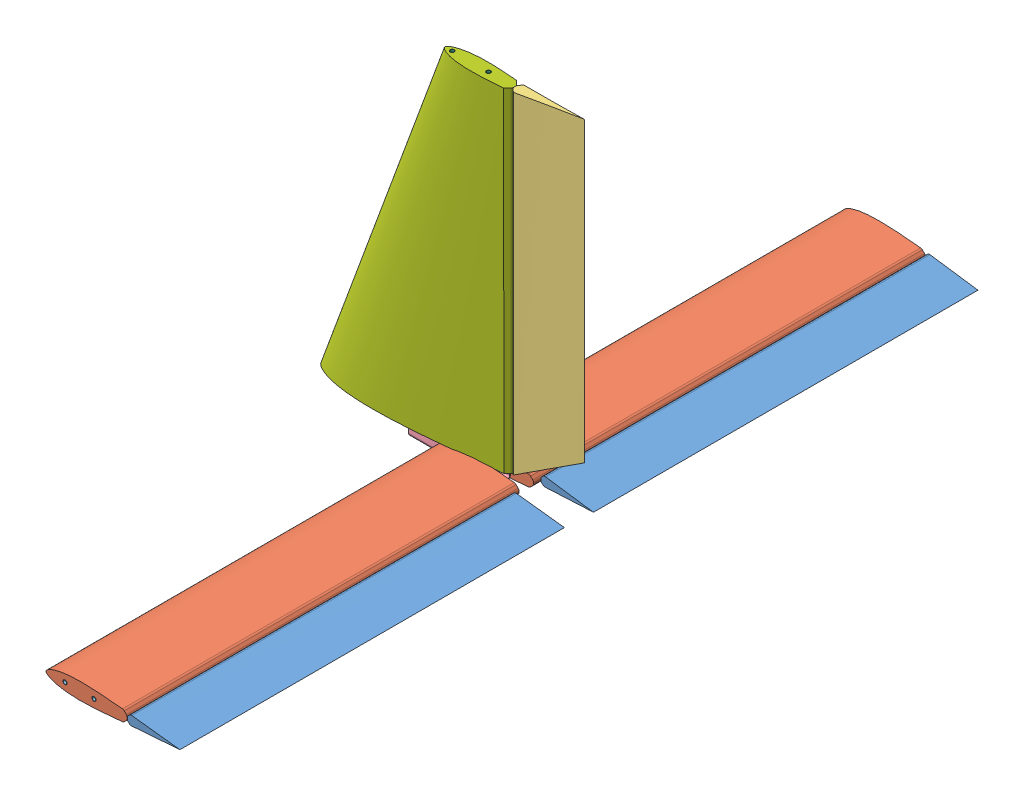
SolidWorks assembly Tail_Assembly, configuration Default. Lengths in mm.
Overall size (451.7 622.57 1397.12).
11 component instances, 7 part files, 24 mates.
Components (placement in the parent):
- Elevator-1: Elevator [Default] at (492.122 379.2937 1582.949) x (0.998942 -0.045988 -0.000487) z (0.000499 0.00026 1) size (92.08 16.15 673.1)
- Horizontal_stabilizer-1: Horizontal_stabilizer [Default] at (491.9754 372.5377 1589.3008) x (0.999999 0.001563 -0.0005) z (0.000499 0.00026 1) size (144.82 29.24 685.8)
- Rudder-1: Rudder [Default] at (492.4867 969.5335 1957.573) x (0.994379 0.000345 -0.105876) z (0.000374 -1 0.000259) size (113.98 20.6 584.38)
- Tail_attachment-1: Tail_attachment [Default] at (593.6259 372.668 1944.8501) x (0.000499 0.00026 1) z (0.000374 -1 0.000259) size (25.4 152.4 25.4)
- Tail_cf_rod_HS-1: Tail_cf_rod_HS [Default] at (576.4486 372.8428 2643.3587) x (0.998942 -0.045988 -0.000487) z (0.045988 0.998942 -0.000282) size (7.24 1397 7.24)
- Tail_cf_rod_VS-1: Tail_cf_rod_VS [Default] at (504.7355 347.2348 1944.9011) x (0.972062 0.000425 0.234724) z (-0.234724 0.000164 0.972062) size (7.24 622.3 7.24)
- Vetical_Stabilizer-1: Vetical_Stabilizer [Default] at (491.8026 969.5299 1944.746) x (1 0.000374 -0.000499) z (0.000374 -1 0.000259) size (337.04 56.71 584.54)
- Elevator-2: Elevator [Default] at (492.3655 375.9774 2306.8498) x (0.999772 -0.02133 -0.000493) z (0.000499 0.00026 1) size (92.08 16.15 673.1)
- Horizontal_stabilizer-2: Horizontal_stabilizer [Default] at (492.3304 372.7224 2300.5007) x (0.999999 0.001563 -0.0005) z (0.000499 0.00026 1) size (144.82 29.24 685.8)
- Tail_cf_rod_HS-2: Tail_cf_rod_HS [Default] at (525.6486 372.8238 2643.3841) x (0.998942 -0.045988 -0.000487) z (0.045988 0.998942 -0.000282) size (7.24 1397 7.24)
- Tail_cf_rod_VS-2: Tail_cf_rod_VS [Default] at (568.2354 347.2585 1944.8694) x (0.993671 0.000401 0.112329) z (-0.11233 0.000216 0.993671) size (7.24 622.3 7.24)
Mates (geometry in assembly coordinates):
- Concentric1: concentric anti-aligned: cylinder of Horizontal_stabilizer-1 through (525.2936 372.6391 1932.1852) axis (-0.000499 -0.00026 -1) radius 3.6; cylinder of Tail_cf_rod_HS-2 through (524.9513 372.4611 1246.3843) axis (0.000499 0.00026 1) radius 3.6195
- Concentric2: concentric anti-aligned: cylinder of Horizontal_stabilizer-2 through (525.6486 372.8238 2643.3851) axis (-0.000499 -0.00026 -1) radius 3.6; cylinder of Tail_cf_rod_HS-2 through (524.9513 372.4611 1246.3843) axis (0.000499 0.00026 1) radius 3.6195
- Coincident1: coincident anti-aligned: circle of Tail_attachment-1; cylinder of Tail_cf_rod_HS-2 through (524.9513 372.4611 1246.3843) axis (0.000499 0.00026 1) radius 3.6195
- Concentric3: concentric anti-aligned: cylinder of Tail_attachment-1 through (576.1063 372.6647 1957.5588) axis (-0.000499 -0.00026 -1) radius 3.6195; cylinder of Tail_cf_rod_HS-1 through (575.7513 372.4801 1246.3589) axis (0.000499 0.00026 1) radius 3.6195
- Concentric4: concentric anti-aligned: cylinder of Horizontal_stabilizer-1 through (576.0936 372.6581 1932.1598) axis (-0.000499 -0.00026 -1) radius 3.6; cylinder of Tail_cf_rod_HS-1 through (575.7513 372.4801 1246.3589) axis (0.000499 0.00026 1) radius 3.6195
- Concentric5: concentric anti-aligned: cylinder of Tail_cf_rod_HS-1 through (575.7513 372.4801 1246.3589) axis (0.000499 0.00026 1) radius 3.6195; cylinder of Horizontal_stabilizer-2 through (576.4486 372.8428 2643.3597) axis (-0.000499 -0.00026 -1) radius 3.6
- Concentric6: concentric anti-aligned: cylinder of Tail_cf_rod_VS-1 through (504.5026 969.5347 1944.7396) axis (0.000374 -1 0.000259) radius 3.6195; cylinder of Vetical_Stabilizer-1 through (504.7213 385.1657 1944.8912) axis (-0.000374 1 -0.000259) radius 3.6195
- Concentric7: concentric aligned: cylinder of Tail_attachment-1 through (568.2212 385.3585 1944.8595) axis (0.000374 -1 0.000259) radius 3.6195; cylinder of Tail_cf_rod_VS-2 through (568.0026 969.5584 1944.7079) axis (0.000374 -1 0.000259) radius 3.6195
- Concentric8: concentric anti-aligned: cylinder of Vetical_Stabilizer-1 through (568.2212 385.1894 1944.8595) axis (-0.000374 1 -0.000259) radius 3.6195; cylinder of Tail_cf_rod_VS-2 through (568.0026 969.5584 1944.7079) axis (0.000374 -1 0.000259) radius 3.6195
- Concentric9: concentric anti-aligned: cylinder of Tail_cf_rod_VS-1 through (504.5026 969.5347 1944.7396) axis (0.000374 -1 0.000259) radius 3.6195; cylinder of Vetical_Stabilizer-1 through (504.7213 385.1657 1944.8912) axis (-0.000374 1 -0.000259) radius 3.6195
- Coincident2: coincident aligned: plane of Horizontal_stabilizer-2 through (492.5015 372.8114 2643.4006) normal (0.000499 0.00026 1); plane of Tail_cf_rod_HS-2 through (525.6486 372.8238 2643.3841) normal (0.000499 0.00026 1)
- Coincident3: coincident anti-aligned: plane of Tail_attachment-1 through (441.2294 380.2343 1957.6242) normal (0.000499 0.00026 1); plane of Horizontal_stabilizer-2 through (492.1592 372.6333 1957.6007) normal (-0.000499 -0.00026 -1)
- Coincident4: coincident anti-aligned: plane of Horizontal_stabilizer-1 through (492.1465 372.6267 1932.2007) normal (0.000499 0.00026 1); plane of Tail_attachment-1 through (441.2168 380.2277 1932.2242) normal (-0.000499 -0.00026 -1)
- Coincident5: coincident anti-aligned: plane of Tail_attachment-1 through (441.2174 385.309 1937.3029) normal (-0.000374 1 -0.000259); plane of Vetical_Stabilizer-1 through (276.8789 385.2495 1945.0049) normal (0.000374 -1 0.000259)
- Coincident6: coincident aligned: plane of Tail_cf_rod_VS-1 through (504.5026 969.5347 1944.7396) normal (-0.000374 1 -0.000259); plane of Vetical_Stabilizer-1 through (491.8026 969.5299 1944.746) normal (-0.000374 1 -0.000259)
- Coincident7: coincident aligned: plane of Vetical_Stabilizer-1 through (491.8026 969.5299 1944.746) normal (-0.000374 1 -0.000259); plane of Tail_cf_rod_VS-2 through (568.0026 969.5584 1944.7079) normal (-0.000374 1 -0.000259)
- Coincident8: coincident aligned: line of Elevator-2 through (634.2765 372.8664 1966.5003) axis (0.000499 0.00026 1); line of Horizontal_stabilizer-2 through (634.272 372.8641 1957.5298) axis (0.000499 0.00026 1)
- Coincident10: coincident aligned: line of Elevator-1 through (633.9152 372.6785 1242.6004) axis (0.000499 0.00026 1); line of Elevator-2 through (634.2765 372.8664 1966.5003) axis (0.000499 0.00026 1)
- Coincident11: coincident aligned: plane of Horizontal_stabilizer-1 through (491.8042 372.4487 1246.4009) normal (-0.000499 -0.00026 -1); circle of Tail_cf_rod_HS-1
- Coincident13: coincident aligned: plane of Elevator-1 through (491.954 379.2064 1246.399) normal (-0.000499 -0.00026 -1); plane of Horizontal_stabilizer-1 through (491.8042 372.4487 1246.4009) normal (-0.000499 -0.00026 -1)
- Coincident14: coincident aligned: plane of Elevator-2 through (492.5335 376.0647 2643.3998) normal (0.000499 0.00026 1); plane of Horizontal_stabilizer-2 through (492.5015 372.8114 2643.4006) normal (0.000499 0.00026 1)
- Coincident15: coincident aligned: line of Rudder-1 through (613.5277 969.5755 1944.6852) axis (0.000374 -1 0.000259); line of Vetical_Stabilizer-1 through (613.5277 969.5755 1944.6852) axis (0.000374 -1 0.000259)
- Coincident16: coincident aligned: plane of Rudder-1 through (492.4867 969.5335 1957.573) normal (-0.000374 1 -0.000259); plane of Vetical_Stabilizer-1 through (491.8026 969.5299 1944.746) normal (-0.000374 1 -0.000259)
- Concentric10: concentric aligned: cylinder of Tail_attachment-1 through (504.7212 385.3347 1944.8912) axis (0.000374 -1 0.000259) radius 3.6195; cylinder of Tail_cf_rod_VS-1 through (504.5026 969.5347 1944.7396) axis (0.000374 -1 0.000259) radius 3.6195
